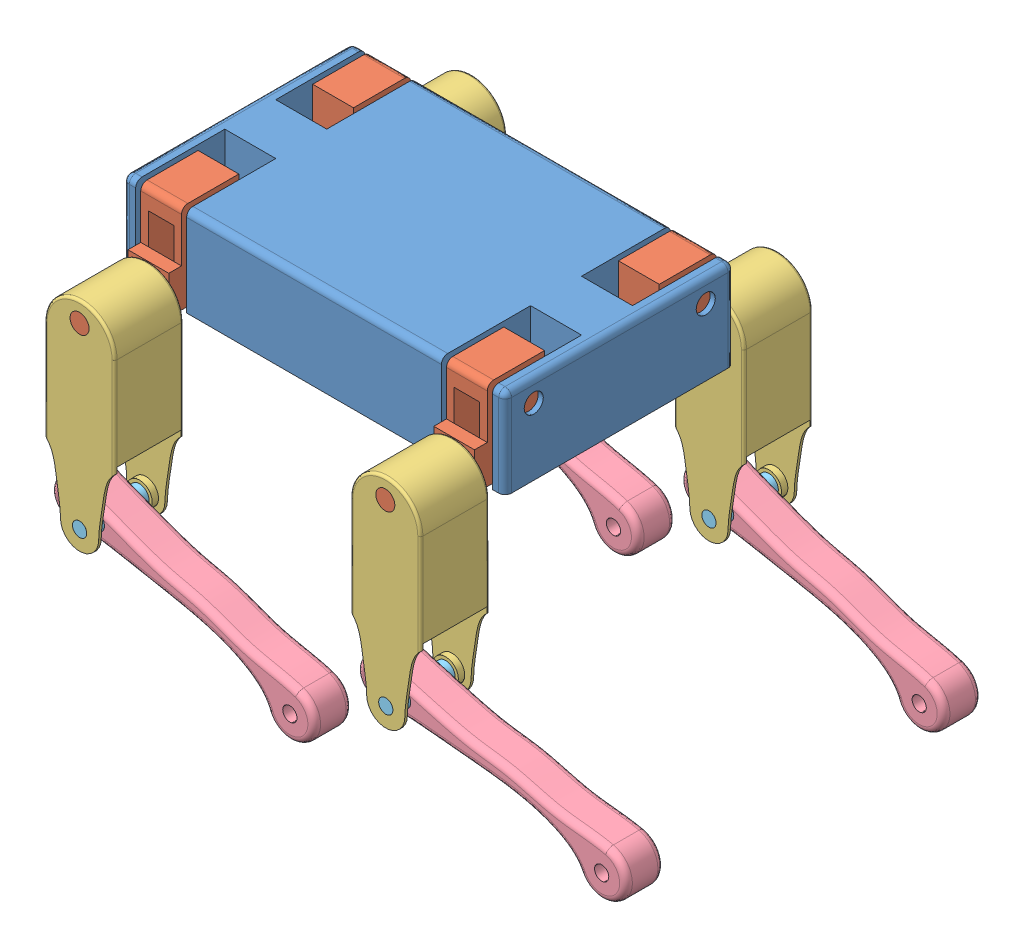
SolidWorks assembly Ensamblaje1, configuration Predeterminado. Lengths in mm.
Overall size (453.33 272.02 308).
17 component instances, 5 part files, 42 mates.
Components (placement in the parent):
- Pieza5-4: Pieza5 [Predeterminado] at (-178.7024 -10.8422 390) x (1 0 0) z (0 1 0) size (300 180 70)
- Pieza3-3: Pieza3 [Predeterminado] at (-168.7024 -10.8422 390) x (0 1 0) z (0 0 -1) size (70 52 109)
- Pieza3-4: Pieza3 [Predeterminado] at (71.2976 -10.8422 390) x (0 1 0) z (0 0 -1) size (70 52 109)
- Pieza3-6: Pieza3 [Predeterminado] at (-128.7024 -10.8422 210) x (0 1 0) z (0 0 1) size (70 52 109)
- Pieza3-7: Pieza3 [Predeterminado] at (111.2976 -10.8422 210) x (0 1 0) z (0 0 1) size (70 52 109)
- Pieza2-1: Pieza2 [Predeterminado] at (-185.7024 -150.8422 400) size (55 170.49 54)
- Pieza1-2: Pieza1 [Predeterminado] at (-10.9574 -239.0799 442) x (-1 0 0) z (0 0 -1) size (206.91 92.47 37.8)
- Pieza4-1: Pieza4 [Predeterminado] at (-148.7024 -135.8422 400) size (15 15 54)
- Pieza1-8: Pieza1 [Predeterminado] at (-10.9574 -239.0799 188) x (-1 0 0) z (0 0 -1) size (206.91 92.47 37.8)
- Pieza2-7: Pieza2 [Predeterminado] at (-185.7024 -150.8422 146) size (55 170.49 54)
- Pieza4-7: Pieza4 [Predeterminado] at (-148.7024 -135.8422 146) size (15 15 54)
- Pieza1-9: Pieza1 [Predeterminado] at (229.0426 -239.0799 188) x (-1 0 0) z (0 0 -1) size (206.91 92.47 37.8)
- Pieza2-8: Pieza2 [Predeterminado] at (54.2976 -150.8422 146) size (55 170.49 54)
- Pieza4-8: Pieza4 [Predeterminado] at (91.2976 -135.8422 146) size (15 15 54)
- Pieza1-10: Pieza1 [Predeterminado] at (238.2922 -225.9775 442) x (-0.995764 -0.091943 0) z (0 0 -1) size (206.91 92.47 37.8)
- Pieza2-9: Pieza2 [Predeterminado] at (54.6753 -150.9318 400) x (0.999997 0.002436 0) z (0 0 1) size (55 170.49 54)
- Pieza4-9: Pieza4 [Predeterminado] at (91.6387 -135.8418 400) size (15 15 54)
Mates (geometry in assembly coordinates):
- Concéntrica5: concentric aligned: cylinder of Pieza2-1 through (-148.7024 -135.8422 474) axis (0 0 -1) radius 5.6; cylinder of Pieza4-1 through (-148.7024 -135.8422 454) axis (0 0 -1) radius 5.6
- Coincidente20: coincident aligned: plane of Pieza2-1 through (-185.7024 -150.8422 454) normal (0 0 1); plane of Pieza4-1 through (-148.7024 -135.8422 454) normal (0 0 1)
- Concéntrica6: concentric anti-aligned: cylinder of Pieza1-2 through (-148.7024 -135.8422 407) axis (0 0 1) radius 5.6; cylinder of Pieza4-1 through (-148.7024 -135.8422 454) axis (0 0 -1) radius 5.6
- Concéntrica7: concentric aligned: cylinder of Pieza2-2 through (-58.3398 -190.7995 2203.0762) axis (0 0 -1) radius 5.6; cylinder of Pieza4-2 through (-58.3398 -190.7995 2183.0762) axis (0 0 -1) radius 5.6
- Coincidente21: coincident aligned: plane of Pieza2-2 through (-95.3398 -205.7995 2183.0762) normal (0 0 1); plane of Pieza4-2 through (-58.3398 -190.7995 2183.0762) normal (0 0 1)
- Concéntrica9: concentric aligned: cylinder of Pieza2-3 through (-138.1459 -107.1634 2207.0578) axis (0 0 -1) radius 5.6; cylinder of Pieza4-3 through (-138.1459 -107.1634 2187.0578) axis (0 0 -1) radius 5.6
- Coincidente22: coincident aligned: plane of Pieza2-3 through (-175.1459 -122.1634 2187.0578) normal (0 0 1); plane of Pieza4-3 through (-138.1459 -107.1634 2187.0578) normal (0 0 1)
- Concéntrica11: concentric aligned: cylinder of Pieza2-4 through (30.4739 -67.3343 2155.0657) axis (0 0 -1) radius 5.6; cylinder of Pieza4-4 through (30.4739 -67.3343 2135.0657) axis (0 0 -1) radius 5.6
- Coincidente23: coincident aligned: plane of Pieza2-4 through (-6.5261 -82.3343 2135.0657) normal (0 0 1); plane of Pieza4-4 through (30.4739 -67.3343 2135.0657) normal (0 0 1)
- Coincidente25: coincident anti-aligned: plane of Pieza1-2 through (-76.9372 -147.9201 442) normal (0 0 1); plane of Pieza4-1 through (-148.7024 -135.8422 442) normal (0 0 -1)
- Concéntrica14: concentric aligned: cylinder of Pieza2-5 through (-296.9461 184.5051 2253.0815) axis (0 0 -1) radius 5.6; cylinder of Pieza4-5 through (-296.9461 184.5051 2233.0815) axis (0 0 -1) radius 5.6
- Coincidente26: coincident aligned: plane of Pieza2-5 through (-333.9461 169.5051 2233.0815) normal (0 0 1); plane of Pieza4-5 through (-296.9461 184.5051 2233.0815) normal (0 0 1)
- Concéntrica16: concentric aligned: cylinder of Pieza2-6 through (-296.9461 184.5051 2253.0815) axis (0 0 -1) radius 5.6; cylinder of Pieza4-6 through (-296.9461 184.5051 2233.0815) axis (0 0 -1) radius 5.6
- Coincidente28: coincident aligned: plane of Pieza2-6 through (-333.9461 169.5051 2233.0815) normal (0 0 1); plane of Pieza4-6 through (-296.9461 184.5051 2233.0815) normal (0 0 1)
- Concéntrica18: concentric aligned: cylinder of Pieza2-7 through (-148.7024 -135.8422 220) axis (0 0 -1) radius 5.6; cylinder of Pieza4-7 through (-148.7024 -135.8422 200) axis (0 0 -1) radius 5.6
- Coincidente30: coincident aligned: plane of Pieza2-7 through (-185.7024 -150.8422 200) normal (0 0 1); plane of Pieza4-7 through (-148.7024 -135.8422 200) normal (0 0 1)
- Concéntrica19: concentric anti-aligned: cylinder of Pieza1-8 through (-148.7024 -135.8422 153) axis (0 0 1) radius 5.6; cylinder of Pieza4-7 through (-148.7024 -135.8422 200) axis (0 0 -1) radius 5.6
- Coincidente31: coincident anti-aligned: plane of Pieza1-8 through (-76.9372 -147.9201 188) normal (0 0 1); plane of Pieza4-7 through (-148.7024 -135.8422 188) normal (0 0 -1)
- Concéntrica20: concentric aligned: cylinder of Pieza2-8 through (91.2976 -135.8422 220) axis (0 0 -1) radius 5.6; cylinder of Pieza4-8 through (91.2976 -135.8422 200) axis (0 0 -1) radius 5.6
- Coincidente32: coincident aligned: plane of Pieza2-8 through (54.2976 -150.8422 200) normal (0 0 1); plane of Pieza4-8 through (91.2976 -135.8422 200) normal (0 0 1)
- Concéntrica21: concentric anti-aligned: cylinder of Pieza1-9 through (91.2976 -135.8422 153) axis (0 0 1) radius 5.6; cylinder of Pieza4-8 through (91.2976 -135.8422 200) axis (0 0 -1) radius 5.6
- Coincidente33: coincident anti-aligned: plane of Pieza1-9 through (163.0628 -147.9201 188) normal (0 0 1); plane of Pieza4-8 through (91.2976 -135.8422 188) normal (0 0 -1)
- Concéntrica22: concentric aligned: cylinder of Pieza2-9 through (91.6387 -135.8418 474) axis (0 0 -1) radius 5.6; cylinder of Pieza4-9 through (91.6387 -135.8418 454) axis (0 0 -1) radius 5.6
- Coincidente34: coincident aligned: plane of Pieza2-9 through (54.6753 -150.9318 454) normal (0 0 1); plane of Pieza4-9 through (91.6387 -135.8418 454) normal (0 0 1)
- Concéntrica23: concentric anti-aligned: cylinder of Pieza1-10 through (91.6387 -135.8418 407) axis (0 0 1) radius 5.6; cylinder of Pieza4-9 through (91.6387 -135.8418 454) axis (0 0 -1) radius 5.6
- Coincidente35: coincident anti-aligned: plane of Pieza1-10 through (164.2103 -141.2703 442) normal (0 0 1); plane of Pieza4-9 through (91.6387 -135.8418 442) normal (0 0 -1)
- Concéntrica24: concentric aligned: cylinder of Pieza3-3 through (-148.7024 4.1578 454) axis (0 0 -1) radius 7.5; cylinder of Pieza2-1 through (-148.7024 4.1578 454) axis (0 0 -1) radius 7.5
- Coincidente36: coincident anti-aligned: plane of Pieza3-3 through (-168.7024 -10.8422 400) normal (0 0 1); plane of Pieza2-1 through (-185.7024 -150.8422 400) normal (0 0 -1)
- Concéntrica25: concentric aligned: cylinder of Pieza3-4 through (91.2976 4.1578 454) axis (0 0 -1) radius 7.5; cylinder of Pieza2-9 through (91.2976 4.1578 454) axis (0 0 -1) radius 7.5
- Coincidente37: coincident anti-aligned: plane of Pieza3-4 through (71.2976 -10.8422 400) normal (0 0 1); plane of Pieza2-9 through (54.6753 -150.9318 400) normal (0 0 -1)
- Concéntrica26: concentric aligned: cylinder of Pieza3-6 through (-148.7024 4.1578 146) axis (0 0 1) radius 7.5; circle of Pieza2-7
- Coincidente38: coincident anti-aligned: plane of Pieza3-6 through (-128.7024 -10.8422 200) normal (0 0 -1); plane of Pieza2-7 through (-185.7024 -150.8422 200) normal (0 0 1)
- Concéntrica27: concentric aligned: cylinder of Pieza3-7 through (91.2976 4.1578 146) axis (0 0 1) radius 7.5; circle of Pieza2-8
- Coincidente39: coincident anti-aligned: plane of Pieza3-7 through (111.2976 -10.8422 200) normal (0 0 -1); plane of Pieza2-8 through (54.2976 -150.8422 200) normal (0 0 1)
- Concéntrica32: concentric aligned: cylinder of Pieza5-4 through (-278.7024 41.6578 367.5) axis (1 0 0) radius 7.5; cylinder of Pieza3-3 through (-198.7024 41.6578 367.5) axis (1 0 0) radius 7.5
- Concéntrica33: concentric anti-aligned: cylinder of Pieza5-4 through (-278.7024 41.6578 232.5) axis (1 0 0) radius 7.5; cylinder of Pieza3-6 through (-98.7024 41.6578 232.5) axis (-1 0 0) radius 7.5
- Concéntrica34: concentric anti-aligned: cylinder of Pieza5-4 through (-278.7024 41.6578 232.5) axis (1 0 0) radius 7.5; cylinder of Pieza3-7 through (141.2976 41.6578 232.5) axis (-1 0 0) radius 7.5
- Concéntrica35: concentric aligned: cylinder of Pieza5-4 through (-278.7024 41.6578 367.5) axis (1 0 0) radius 7.5; cylinder of Pieza3-4 through (41.2976 41.6578 367.5) axis (1 0 0) radius 7.5
- Coincidente45: coincident aligned: plane of Pieza3-6 through (-174.7024 -10.8422 300) normal (-1 0 0)
- Coincidente46: coincident aligned: plane of Pieza3-3 through (-174.7024 -10.8422 300) normal (-1 0 0)
- Coincidente53: coincident anti-aligned: plane of Pieza3-4 through (65.2976 -10.8422 300) normal (-1 0 0)
- Coincidente54: coincident anti-aligned: plane of Pieza3-7 through (65.2976 -10.8422 300) normal (-1 0 0)
